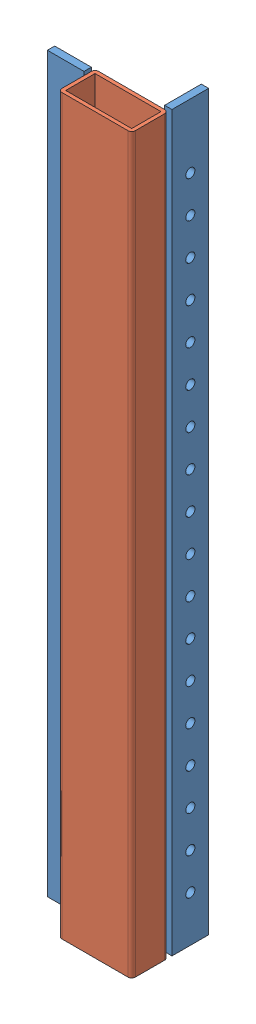
SolidWorks assembly Стойка2, configuration По умолчанию. Lengths in mm.
Overall size (62 400 42).
3 component instances, 2 part files, 6 mates.
Components (placement in the parent):
- Полоса204-1: Полоса204 [По умолчанию] at (18 0 -22) x (0 0 -1) z (1 0 0) size (20 400 4)
- Профиль2040-1: Профиль2040 [По умолчанию] at origin size (40 400 20)
- Полоса204-2: Полоса204 [По умолчанию] at (-32 0 -8) x (-1 0 0) z (0 0 -1) size (20 400 4)
Mates (geometry in assembly coordinates):
- Совпадение2: coincident aligned: plane of Полоса204-1 through (20 400 32) normal (1 0 0); plane of Профиль2040-1 through (20 400 -8) normal (1 0 0)
- Расстояние1: distance = 2 mm anti-aligned: plane of Полоса204-1 through (16 400 -12) normal (0 0 1); plane of Профиль2040-1 through (-18 400 -10) normal (0 0 -1)
- Совпадение4: coincident aligned: plane of Полоса204-1 through (18 0 22) normal (0 -1 0); plane of Профиль2040-1 through (-18 0 8) normal (0 -1 0)
- Совпадение5: coincident aligned: plane of Профиль2040-1 through (-18 400 -10) normal (0 0 -1); plane of Полоса204-2 through (-22 400 -10) normal (0 0 -1)
- Расстояние2: distance = 2 mm anti-aligned: plane of Полоса204-2 through (-22 400 -6) normal (1 0 0); plane of Профиль2040-1 through (-20 400 -8) normal (-1 0 0)
- Совпадение7: coincident aligned: plane of Профиль2040-1 through (-18 0 8) normal (0 -1 0); plane of Полоса204-2
